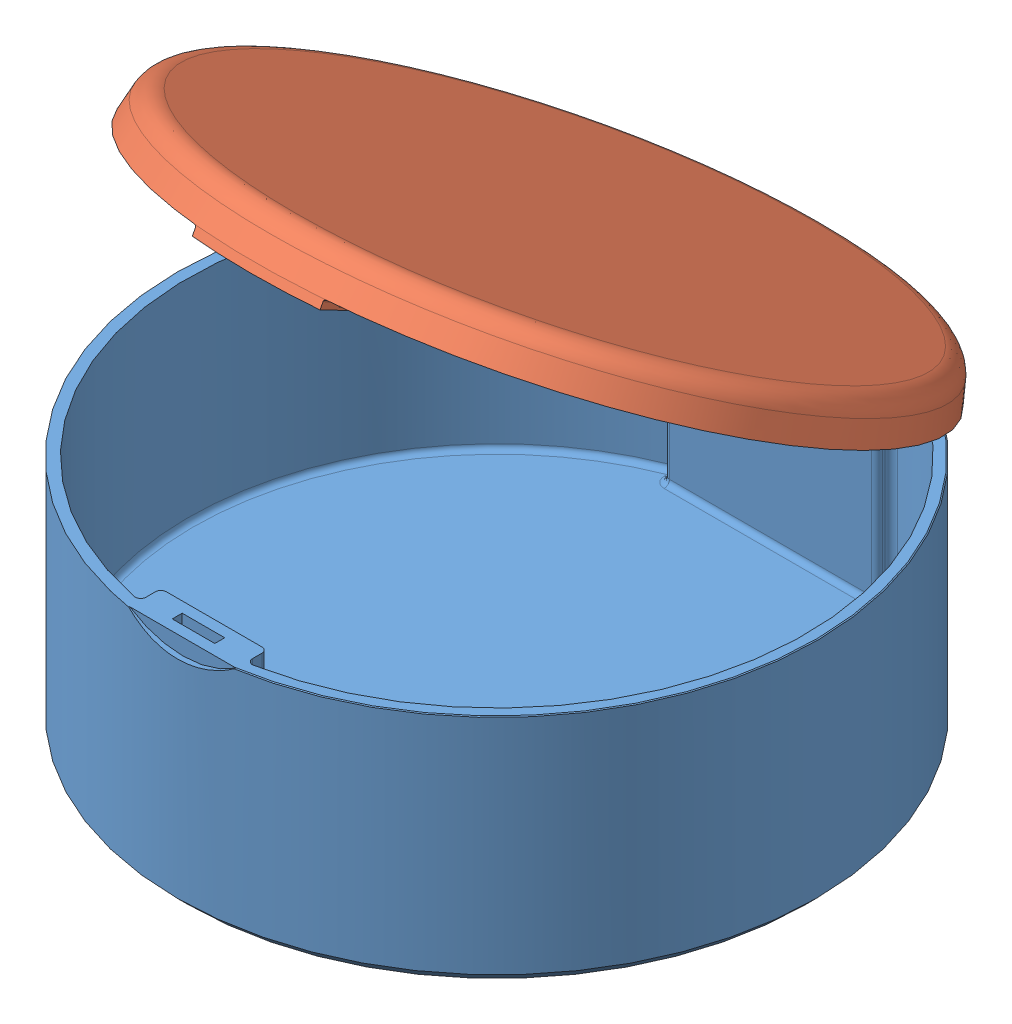
SolidWorks assembly robot vacuum, configuration Default. Lengths in mm.
Overall size (300 370.69 521.34).
2 component instances, 2 part files, 6 mates.
Components (placement in the parent):
- buttom (new)-1: buttom (new) [Default] at origin size (300 112.56 510.7)
- top-1: top [Default] at (0 95.7665 -18.1004) x (1 0 0) z (0 0.457413 0.889255) size (299 30 537.26)
Mates (geometry in assembly coordinates):
- Distance1: distance = 0 mm aligned: plane of assembly through (0 0 0) normal (1 0 0); plane of buttom (new)-1 through (0 0 0) normal (1 0 0)
- Distance2: distance = 0 mm aligned: plane of buttom (new)-1 through (0 0 0) normal (0 1 0); plane of assembly through (0 0 0) normal (0 1 0)
- Distance3: distance = 0 mm aligned: plane of buttom (new)-1 through (0 0 0) normal (0 0 1); plane of assembly through (0 0 0) normal (0 0 1)
- Concentric10: concentric aligned: circle of buttom (new)-1; circle of top-1
- Distance6: distance = 1 mm anti-aligned: plane of top-1 through (-35 24.73 -134.34) normal (-1 0 0); plane of buttom (new)-1 through (-36 20 -138.6066) normal (1 0 0)
- Parallel2: parallel anti-aligned: plane of buttom (new)-1 through (0 30 0) normal (0 1 0); plane of top-1
